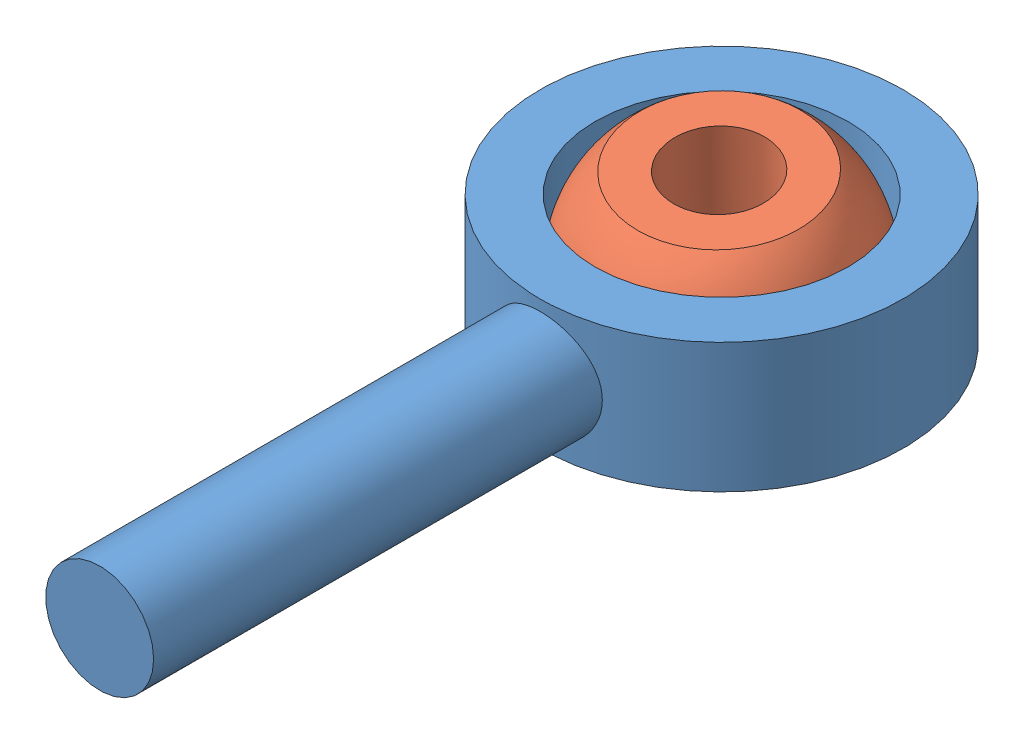
SolidWorks assembly rod_and_bearing_assm, configuration 기본. Lengths in mm.
Overall size (13.45 7.96 29.78).
2 component instances, 2 part files, 1 mates.
Components (placement in the parent):
- rod-1: rod [기본] at (2.4038 -0.6789 21.6125) size (13.45 4.8 29.78)
- bearing-1: bearing [기본] at (2.4038 -0.6789 21.6125) x (0.335707 -0.097345 0.936923) z (0.940271 -0.025021 -0.339506) size (9.35 6.85 9.35)
Mates (geometry in assembly coordinates):
- 일치1: coincident: circle of rod-1; sphere of bearing-1
